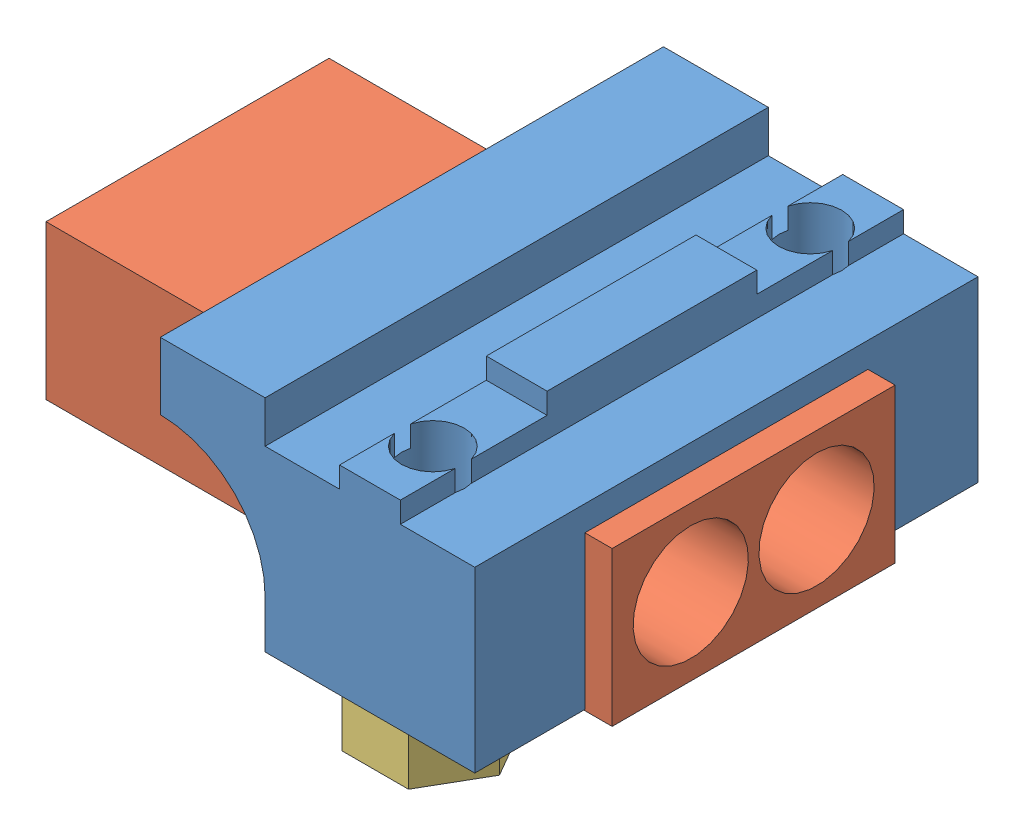
SolidWorks assembly BatteryConnectorFemaleMakerBeamSupport_WithConnectorAssembly, configuration Default. Lengths in mm.
Overall size (27 13 24).
4 component instances, 3 part files, 7 mates.
Components (placement in the parent):
- BatteryConnectorFemaleMakerBeamSupport_Bottom-1: BatteryConnectorFemaleMakerBeamSupport_Bottom [Default] at (8.3596 9.1977 10.8161) size (15 10.5 24)
- BatteryConnectorFemale-1: BatteryConnectorFemale [Default] at (1.1596 12.8227 10.8161) x (0 0 1) z (0 -1 0) size (13.5 27 9.95)
- Nut3mm-1: Nut3mm [Default] at (8.3596 9.1977 1.8161) x (1 0 0) z (0 -1 0) size (6.35 5.5 2.5)
- Nut3mm-3: Nut3mm [Default] at (8.3596 9.1977 19.8161) x (1 0 0) z (0 -1 0) size (6.35 5.5 2.5)
Mates (geometry in assembly coordinates):
- Coincident1: coincident anti-aligned: plane of BatteryConnectorFemaleMakerBeamSupport_Bottom-1 through (8.3596 16.4977 10.8161) normal (0 -1 0); plane of BatteryConnectorFemale-1 through (1.1596 16.4977 10.8161) normal (0 1 0)
- Coincident2: coincident anti-aligned: plane of BatteryConnectorFemaleMakerBeamSupport_Bottom-1 through (13.3596 16.4977 4.0661) normal (0 0 1); plane of BatteryConnectorFemale-1 through (14.6596 9.1477 4.0661) normal (0 0 -1)
- Coincident3: coincident anti-aligned: plane of BatteryConnectorFemaleMakerBeamSupport_Bottom-1 through (1.3596 17.9977 15.0661) normal (-1 0 0); plane of BatteryConnectorFemale-1 through (1.3596 16.4977 15.3161) normal (1 0 0)
- Coincident4: coincident anti-aligned: plane of BatteryConnectorFemaleMakerBeamSupport_Bottom-1 through (3.3596 9.1977 22.8161) normal (0 -1 0); plane of Nut3mm-1 through (8.3596 9.1977 1.8161) normal (0 1 0)
- Concentric3: concentric aligned: cylinder of BatteryConnectorFemaleMakerBeamSupport_Bottom-1 through (8.3596 9.1977 1.8161) axis (0 1 0) radius 1.5; cylinder of Nut3mm-1 through (8.3596 6.6977 1.8161) axis (0 1 0) radius 1.25
- Coincident5: coincident anti-aligned: plane of BatteryConnectorFemaleMakerBeamSupport_Bottom-1 through (3.3596 9.1977 22.8161) normal (0 -1 0); plane of Nut3mm-3 through (8.3596 9.1977 19.8161) normal (0 1 0)
- Concentric5: concentric anti-aligned: circle of BatteryConnectorFemaleMakerBeamSupport_Bottom-1; circle of Nut3mm-3
